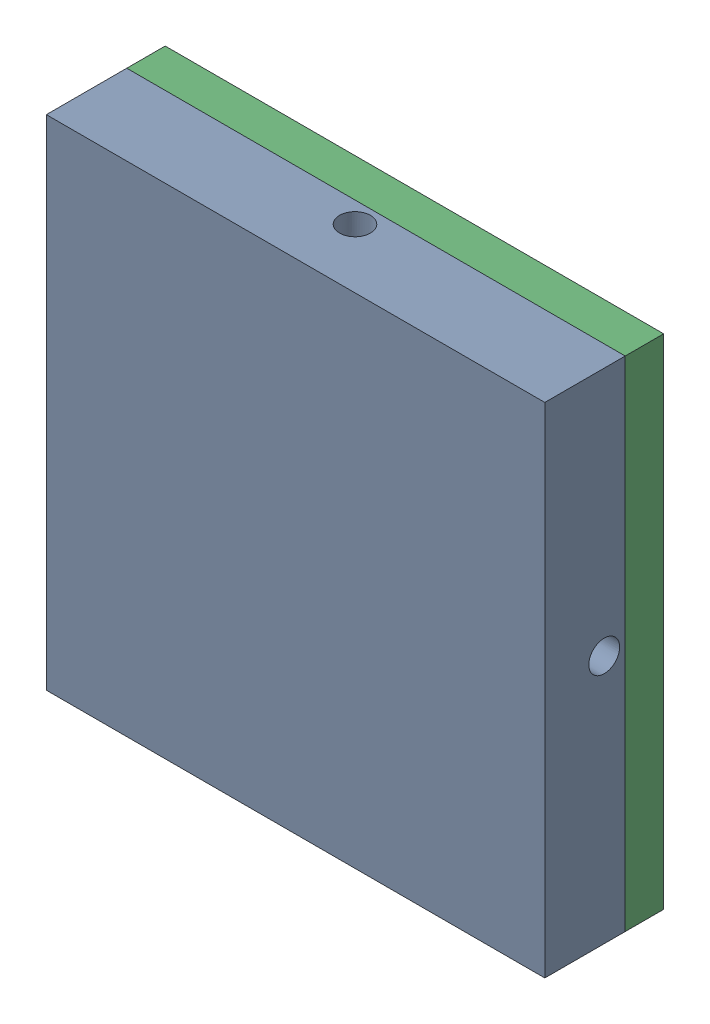
SolidWorks assembly Aft Bulkhead Jig Visualization, configuration Default. Lengths in mm.
Overall size (113.16 113.16 27.08).
3 component instances, 3 part files, 6 mates.
Components (placement in the parent):
- SS_Aft_Bulkhead_Jig_p1-1: SS_Aft_Bulkhead_Jig_p1 [Default] at (-27.7347 8.5331 13.648) size (113.16 113.16 27.08)
- SS_Airbrakes_Bulkhead-1: SS_Airbrakes_Bulkhead [Default] at (-27.7347 8.5331 39.048) x (-1 0 0) z (0 -1 0) size (99.03 9.52 99.03)
- SS_Aft_Bulkhead_Jig_p2-1: SS_Aft_Bulkhead_Jig_p2 [Default] at (-27.7347 8.5331 4.123) x (-1 0 0) z (0 0 -1) size (113.16 113.16 18.13)
Mates (geometry in assembly coordinates):
- Concentric1: concentric: cylinder of SS_Aft_Bulkhead_Jig_p1-1 through (-27.7347 8.5331 4.123) axis (0 0 1) radius 3.0162; cylinder of SS_Airbrakes_Bulkhead-1 through (-27.7347 8.5331 48.573) axis (0 0 -1) radius 3.3
- Coincident4: coincident: plane of SS_Aft_Bulkhead_Jig_p1-1 through (-27.7347 8.5331 13.648) normal (0 0 -1); plane of SS_Airbrakes_Bulkhead-1 through (-27.7347 8.5331 13.648) normal (0 0 1)
- Concentric3: concentric aligned: cylinder of SS_Aft_Bulkhead_Jig_p1-1 through (-27.7347 65.1126 8.8855) axis (0 -1 0) radius 3.5; cylinder of SS_Airbrakes_Bulkhead-1 through (-27.7347 -40.9842 8.8855) axis (0 -1 0) radius 1.65
- Concentric4: concentric: cylinder of SS_Aft_Bulkhead_Jig_p1-1 through (-27.7347 8.5331 4.123) axis (0 0 1) radius 3.0162; cylinder of SS_Aft_Bulkhead_Jig_p2-1 through (-27.7347 8.5331 -4.6082) axis (0 0 1) radius 3.175
- Concentric5: concentric: circle of SS_Aft_Bulkhead_Jig_p1-1; cylinder of SS_Aft_Bulkhead_Jig_p2-1 through (16.1438 52.4116 13.521) axis (0 0 -1) radius 3.175
- Coincident5: coincident anti-aligned: plane of SS_Aft_Bulkhead_Jig_p1-1 through (-27.7347 8.5331 4.123) normal (0 0 -1); plane of SS_Aft_Bulkhead_Jig_p2-1 through (-27.7347 8.5331 4.123) normal (0 0 1)
